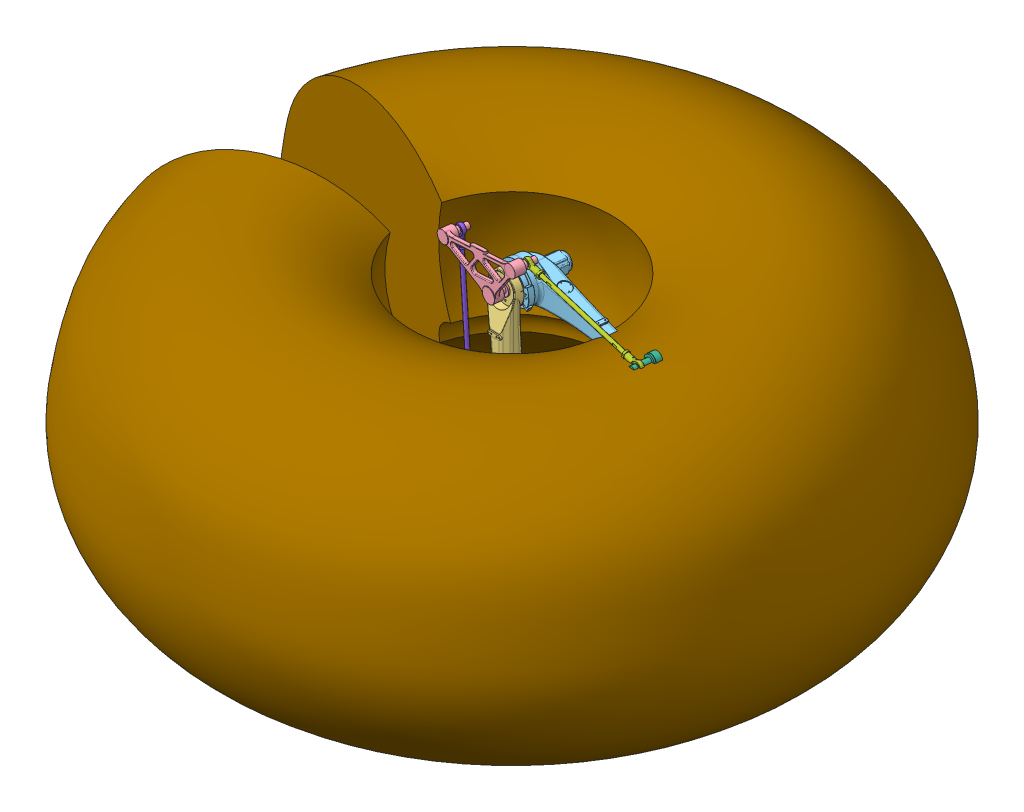
SolidWorks assembly ER12-C604数模（带包络图Solidworks）, configuration 默认. Lengths in mm.
Overall size (4110.94 1535.08 4110.94).
10 component instances, 9 part files, 3 mates.
Components (placement in the parent):
- 复件 ER12数模^ER12-C604数模（带包络图Solidworks）-1: 复件 ER12数模^ER12-C604数模（带包络图Solidworks） [默认] at (267.6342 -340.8155 769.7693) size (1263.82 1313.08 530.22) (virtual, flexible)
  - 复件 ER12底座（2017-11-13）^复件 ER12数模_ER12-C604数模（带包络图Solidworks）-1: 复件 ER12底座（2017-11-13）^复件 ER12数模_ER12-C604数模（带包络图Solidworks） [默认] at (19.8346 -30.4643 16) size (484 225 396) (virtual)
  - 复件 ER12转座^复件 ER12数模_ER12-C604数模（带包络图Solidworks）-1: 复件 ER12转座^复件 ER12数模_ER12-C604数模（带包络图Solidworks） [默认] at (269.2508 -124.95 28.6314) x (0.993388 0 0.114809) z (-0.114809 0 0.993388) size (532.16 372.4 430.51) (virtual)
  - 复件 ER12大臂（2017-11-13）^复件 ER12数模_ER12-C604数模（带包络图Solidworks）-2: 复件 ER12大臂（2017-11-13）^复件 ER12数模_ER12-C604数模（带包络图Solidworks） [默认] at (-481.0016 724.3713 1445.503) x (-0.990549 -0.075548 -0.114481) z (0.114809 0 -0.993388) size (215.49 852.5 152.45) (virtual)
  - 复件 ER12连杆2^复件 ER12数模_ER12-C604数模（带包络图Solidworks）-1: 复件 ER12连杆2^复件 ER12数模_ER12-C604数模（带包络图Solidworks） [默认] at (152.5252 1095.457 158.3071) x (0.993388 0.000019 0.114809) z (-0.114809 0 0.993388) size (438.19 237.02 113.5) (virtual)
  - 复件 ER12小臂部分^复件 ER12数模_ER12-C604数模（带包络图Solidworks）-2: 复件 ER12小臂部分^复件 ER12数模_ER12-C604数模（带包络图Solidworks） [默认] at (-303.0356 681.3214 255.4579) x (0.981404 -0.15486 0.113424) z (-0.114809 0 0.993388) size (770.64 229.78 254.8) (virtual)
  - 复件 ER12手腕部分^复件 ER12数模_ER12-C604数模（带包络图Solidworks）-3: 复件 ER12手腕部分^复件 ER12数模_ER12-C604数模（带包络图Solidworks） [默认] at (738.4682 1021.4204 814.8825) x (0.993388 0.000019 0.114809) z (0.114809 0 -0.993388) size (243.51 289.02 255.72) (virtual)
  - 复件 ER12连杆3^复件 ER12数模_ER12-C604数模（带包络图Solidworks）-1: 复件 ER12连杆3^复件 ER12数模_ER12-C604数模（带包络图Solidworks） [默认] at (15.0639 1211.9115 622.3318) x (0.153836 0.987936 0.017779) z (0.981404 -0.15486 0.113424) size (46 31.07 676) (virtual)
  - 复件 ER12连杆一^复件 ER12数模_ER12-C604数模（带包络图Solidworks）-1: 复件 ER12连杆一^复件 ER12数模_ER12-C604数模（带包络图Solidworks） [默认] at (-170.9399 1619.9969 604.13) x (0.990548 0.075553 0.114481) z (0.075053 -0.997142 0.008674) size (46 60 726) (virtual)
- 复件 ER12-C604包络块^ER12-C604数模（带包络图Solidworks）-1: 复件 ER12-C604包络块^ER12-C604数模（带包络图Solidworks） [默认] at (-3376.6888 -93.0578 278.9798) x (-0.965926 0 -0.258819) z (0.258819 0 -0.965926) size (3356.57 1429.67 3356.57) (virtual)
Mates (geometry in assembly coordinates):
- 重合1: coincident anti-aligned: axis of 复件 ER12数模^ER12-C604数模（带包络图Solidworks）-1/复件 ER12底座（2017-11-13）^复件 ER12数模_ER12-C604数模（带包络图Solidworks）-1 through (261.2751 -231.0578 1253.7693) axis (0 -1 0); axis of 复件 ER12-C604包络块^ER12-C604数模（带包络图Solidworks）-1 through (261.2751 -1231.9652 1253.7693) axis (0 1 0)
- 距离1: distance = 222 mm aligned: plane of 复件 ER12数模^ER12-C604数模（带包络图Solidworks）-1/复件 ER12底座（2017-11-13）^复件 ER12数模_ER12-C604数模（带包络图Solidworks）-1 through (261.2751 -456.0578 1253.7693) normal (0 -1 0); plane of 复件 ER12-C604包络块^ER12-C604数模（带包络图Solidworks）-1 through (-3376.6888 -678.0578 278.9798) normal (0 -1 0)
- 角度2: planar angle = 0.261799 rad aligned: plane of assembly through (0 0 1253.7693) normal (0 0 -1); plane of 复件 ER12-C604包络块^ER12-C604数模（带包络图Solidworks）-1 through (-528.344 -299.8636 1465.3471) normal (-0.258819 0 -0.965926)
